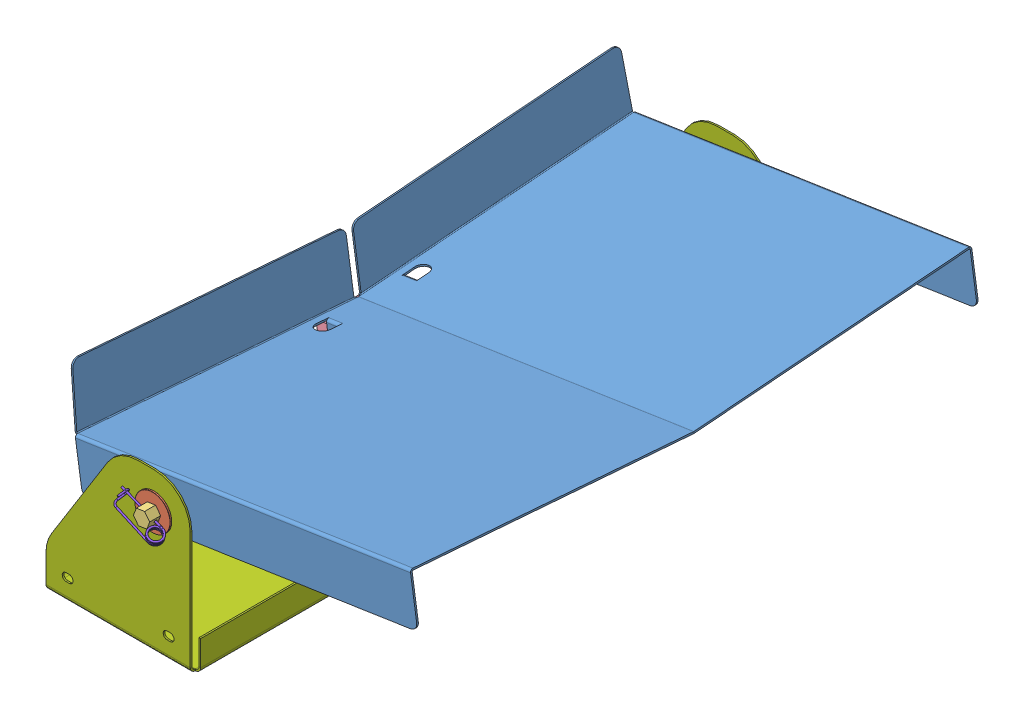
SolidWorks assembly GE-19092, configuration Default. Lengths in mm.
Overall size (322.54 220.42 546.4).
16 component instances, 11 part files, 42 mates.
Components (placement in the parent):
- GE-19085-1: GE-19085 [Magnet_Tray] at (102.7953 126.0608 0) x (0 0 -1) z (0.9887 0.149909 0) size (494.19 94.69 300.92)
- GE-19215-1: GE-19215 [Default] at (31.75 106.5212 249.1842) x (-0.624175 0.781284 0) z (0 0 1) size (31.12 31.12 7.93)
- GE-19215-2: GE-19215 [Default] at (31.75 106.5212 -249.1842) x (0.624175 -0.781284 0) z (0 0 -1) size (31.12 31.12 7.93)
- GE-19096-1: GE-19096 [Default] at (31.75 106.5212 0) x (0.364525 0.931194 0) z (0 0 1) size (14.66 12.7 533.4)
- GE-19099-1: GE-19099 [Default] at (-29.6036 90.187 -0.8681) x (0 0 1) z (-0.982197 -0.187855 0) size (63.5 12.7 38.1)
- Magnet-1: Magnet [Default] at (-29.9177 90.4396 -0.3125) x (0 0 -1) z (-0.984808 -0.173648 0) size (80 24.35 38.1)
- GE-19097-1: GE-19097 [Default] at (-44.45 0 0) x (0 0 1) z (-1 0 0) size (79.38 68.58 38.1)
- GE-19095-2: GE-19095 [Default] x (0 0 1) z (-1 0 0) size (511.18 139.7 136.21)
- pin_bentwire_.0625_1.0625-3: pin_bentwire_.0625_1.0625 [90174A113] at (43.8036 101.9377 -260.4308) x (-0.230622 -0.809824 0.539443) z (-0.952835 0.30035 0.043538) size (6.66 13.94 44.51)
- pin_bentwire_.0625_1.0625-4: pin_bentwire_.0625_1.0625 [90174A113] at (43.7054 101.6867 260.3098) x (0.424884 0.864692 0.267921) z (-0.89993 0.435498 0.021624) size (6.66 13.94 44.51)
- hex_.25_20_.75-2: hex_.25_20_.75 [hex_.25_20_.75] at (-25.4 6.1119 -25.4) x (0 1 0) z (0 0 1) size (23.02 12.83 11.11)
- hex_.25_20_.75-3: hex_.25_20_.75 [hex_.25_20_.75] at (-25.4 6.1119 25.4) x (0 1 0) z (0.188455 0 0.982082) size (23.02 12.83 11.11)
- VHB_Tape-1: VHB_Tape [Default] at (-37.9759 63.0035 -0.3075) x (0 0 -1) z (0.984808 0.173648 0) size (80.01 1.27 12.7)
- VHB_Tape-2: VHB_Tape [Default] at (-12.9618 67.4142 -0.3075) x (0 0 1) z (-0.984808 -0.173648 0) size (80.01 1.27 12.7)
- round_hex_10_32_.625_full-1: round_hex_10_32_.625_full [91306A274] at (-30.7965 96.4239 39.6059) x (0.999933 0.011616 0) z (0 0 1) size (9.17 9.17 18.62)
- round_hex_10_32_.625_full-2: round_hex_10_32_.625_full [91306A274] at (-30.7965 96.4239 -41.342) x (0.523381 -0.852099 0) z (0 0 -1) size (9.17 9.17 18.62)
Mates (geometry in assembly coordinates):
- Coincident13: coincident: plane of GE-19085-1 through (102.7953 126.0608 0) normal (0 0 -1); plane of assembly through (0 0 0) normal (0 0 1)
- Coincident42: coincident: plane of assembly; plane of assembly; plane of Magnet-1 through (-44.45 63.1515 39.6875) normal (0 0 1); plane of GE-19097-1 through (-44.45 0 39.6875) normal (0 0 1)
- Coincident43: coincident: line of assembly; plane of assembly; line of Magnet-1 through (-44.45 63.1515 39.6875) axis (0 0 -1); plane of GE-19097-1 through (-44.45 61.8619 39.6875) normal (-1 0 0)
- Concentric13: concentric: cylinder of assembly; cylinder of assembly; cylinder of GE-19215-2 through (31.75 106.5212 -257.1115) axis (0 0 1) radius 14.2875; cylinder of GE-19095-2 through (31.75 106.5212 -255.5875) axis (0 0 1) radius 14.2812
- Concentric14: concentric: cylinder of assembly; cylinder of assembly; cylinder of GE-19215-1 through (31.75 106.5212 257.1115) axis (0 0 -1) radius 14.2875; cylinder of GE-19095-2 through (31.75 106.5212 -255.5875) axis (0 0 1) radius 14.2812
- Coincident48: coincident: plane of assembly through (0 0 0) normal (0 0 1); plane of GE-19095-2 through (0 0 0) normal (0 0 1); plane of assembly
- Coincident49: coincident: plane of assembly through (0 0 0) normal (1 0 0); plane of GE-19095-2 through (0 0 0) normal (-1 0 0); plane of assembly
- Coincident50: coincident: plane of assembly through (0 0 0) normal (0 1 0); plane of GE-19095-2 through (0 0 0) normal (0 1 0); plane of assembly
- Concentric15: concentric: cylinder of assembly; cylinder of assembly; cylinder of GE-19097-1 through (-25.4 0 25.4) axis (0 -1 0) radius 2.5527; cylinder of GE-19095-2 through (-25.4 0 25.4) axis (0 1 0) radius 3.2639
- Concentric16: concentric: cylinder of assembly; cylinder of assembly; cylinder of GE-19097-1 through (-25.4 0 -25.4) axis (0 -1 0) radius 2.5527; cylinder of GE-19095-2 through (-25.4 0 -25.4) axis (0 1 0) radius 3.2639
- Coincident51: coincident: plane of assembly; plane of assembly; plane of GE-19097-1 through (-44.45 0 39.6875) normal (0 -1 0); plane of GE-19095-2 through (0 0 0) normal (0 1 0)
- Tangent9: tangent: plane of assembly; plane of GE-19096-1 through (36.3267 100.7926 266.7) normal (0.931194 -0.364525 0); face of pin_bentwire_.0625_1.0625-3
- Tangent12: tangent: plane of assembly; plane of GE-19096-1 through (36.3267 100.7926 266.7) normal (0.931194 -0.364525 0); face of pin_bentwire_.0625_1.0625-4
- Coincident56: coincident: unknown of ?; plane of ? through (-29.6283 89.2521 -0.3125) normal (-0.173648 0.984808 0)
- Coincident61: coincident: plane of assembly; plane of assembly; plane of GE-19215-2 through (40.4697 95.6067 -255.5875) normal (0 0 1); plane of GE-19095-2 through (0 0 -255.5875) normal (0 0 -1)
- Coincident63: coincident: plane of assembly; plane of assembly; plane of GE-19215-1 through (23.0303 117.4358 255.5875) normal (0 0 -1); plane of GE-19095-2 through (0 0 255.5875) normal (0 0 1)
- Coincident64: coincident: plane of assembly; plane of assembly; plane of GE-19215-1 through (27.1733 112.2499 257.1115) normal (0.149909 -0.9887 0); plane of GE-19096-1 through (34.4228 113.3491 266.7) normal (-0.149909 0.9887 0)
- Coincident65: coincident: plane of GE-19085-1 through (27.1733 112.2499 252.7917) normal (0.149909 -0.9887 0); plane of GE-19215-1 through (27.1733 112.2499 257.1115) normal (0.149909 -0.9887 0)
- Coincident66: coincident: plane of assembly; plane of assembly; plane of GE-19215-1 through (27.1733 112.2499 257.1115) normal (0.149909 -0.9887 0); plane of GE-19215-2 through (34.4228 113.3491 -257.1115) normal (0.149909 -0.9887 0)
- Coincident67: coincident: plane of assembly; plane of assembly; plane of GE-19215-1 through (24.5005 105.4221 257.1115) normal (0.931194 -0.364525 0); plane of GE-19096-1 through (27.1733 112.2499 266.7) normal (-0.931194 0.364525 0)
- Coincident68: coincident: plane of GE-19085-1 through (24.3936 105.1489 252.7917) normal (0.931194 -0.364525 0); plane of GE-19096-1 through (27.1733 112.2499 266.7) normal (-0.931194 0.364525 0)
- Width2: width: plane of assembly; plane of assembly; plane of assembly; plane of assembly; plane of GE-19096-1 through (31.75 106.5212 266.7) normal (0 0 1); plane of GE-19096-1 through (31.75 106.5212 -266.7) normal (0 0 -1); plane of GE-19095-2 through (0 0 -255.5875) normal (0 0 -1); plane of GE-19095-2 through (0 0 255.5875) normal (0 0 1)
- Coincident71: coincident: unknown of ?; plane of ? through (-29.6283 89.2521 -0.3125) normal (-0.173648 0.984808 0)
- Concentric28: concentric: cylinder of assembly; cylinder of assembly; cylinder of GE-19096-1 through (37.6631 104.2065 -260.35) axis (-0.931194 0.364525 0) radius 1.2573; cylinder of pin_bentwire_.0625_1.0625-3 through (41.6769 102.6353 -260.35) axis (-0.931194 0.364525 0) radius 0.7366
- Concentric29: concentric: cylinder of assembly; cylinder of assembly; cylinder of GE-19096-1 through (37.6631 104.2065 260.35) axis (-0.931194 0.364525 0) radius 1.2573; cylinder of pin_bentwire_.0625_1.0625-4 through (41.6769 102.6353 260.35) axis (-0.931194 0.364525 0) radius 0.7366
- Concentric30: concentric: cylinder of assembly; cylinder of assembly; cylinder of GE-19097-1 through (-25.4 0 -25.4) axis (0 -1 0) radius 2.5527; cylinder of hex_.25_20_.75-2 through (-25.4 -1.4287 -25.4) axis (0 1 0) radius 3.175
- Coincident72: coincident: plane of assembly; plane of assembly; plane of GE-19095-2 through (0 -1.4287 0) normal (0 -1 0); plane of hex_.25_20_.75-2 through (-28.6079 -1.4287 -19.8438) normal (0 1 0)
- Concentric31: concentric: cylinder of assembly; cylinder of assembly; cylinder of GE-19097-1 through (-25.4 0 25.4) axis (0 -1 0) radius 2.5527; cylinder of hex_.25_20_.75-3 through (-25.4 -1.4287 25.4) axis (0 1 0) radius 3.175
- Coincident73: coincident: plane of assembly; plane of assembly; plane of GE-19095-2 through (0 -1.4287 0) normal (0 -1 0); plane of hex_.25_20_.75-3 through (-27.5033 -1.4287 31.4612) normal (0 1 0)
- Width4: width: plane of GE-19099-1 through (-50.7002 99.0822 30.8819) normal (0 0 1); plane of GE-19099-1 through (-50.7002 99.0822 -32.6181) normal (0 0 -1); plane of GE-19085-1 through (97.5504 160.653 -35.6016) normal (0 0 -1); plane of GE-19085-1 through (97.5455 160.6853 33.8655) normal (0 0 1)
- Coincident76: coincident: plane of assembly; plane of assembly; plane of Magnet-1 through (-25.6894 66.4595 -0.3125) normal (0.173648 -0.984808 0); plane of VHB_Tape-2 through (-13.1824 68.6649 -0.3075) normal (-0.173648 0.984808 0)
- Coincident77: coincident: plane of assembly; plane of assembly; plane of Magnet-1 through (-6.9288 69.7675 39.6875) normal (0.984808 0.173648 0); plane of VHB_Tape-2 through (-6.9288 69.7675 -40.3125) normal (0.984808 0.173648 0)
- Coincident78: coincident: plane of assembly; plane of assembly; plane of Magnet-1 through (-44.45 63.1515 -40.3125) normal (0 0 -1); plane of VHB_Tape-2 through (-19.4359 67.5622 -40.3125) normal (0 0 -1)
- Coincident79: coincident: plane of assembly; plane of assembly; plane of Magnet-1 through (-25.6894 66.4595 -0.3125) normal (0.173648 -0.984808 0); plane of VHB_Tape-1 through (-38.1965 64.2542 -0.3075) normal (-0.173648 0.984808 0)
- Coincident80: coincident: plane of assembly; plane of assembly; plane of Magnet-1 through (-44.45 63.1515 39.6875) normal (-0.984808 -0.173648 0); plane of VHB_Tape-1 through (-44.45 63.1515 39.6975) normal (-0.984808 -0.173648 0)
- Coincident81: coincident: plane of assembly; plane of assembly; plane of Magnet-1 through (-44.45 63.1515 -40.3125) normal (0 0 -1); plane of VHB_Tape-1 through (-31.9429 65.3569 -40.3125) normal (0 0 -1)
- Coincident82: coincident: plane of assembly; plane of assembly; plane of GE-19097-1 through (-6.35 68.58 39.6875) normal (-0.173648 0.984808 0); plane of VHB_Tape-2 through (-12.9618 67.4142 -0.3075) normal (0.173648 -0.984808 0)
- Distance1: distance = 3.175 mm: plane of round_hex_10_32_.625_full-1 through (-30.7432 91.8395 37.0405) normal (0 0 -1); plane of GE-19085-1 through (97.5455 160.6853 33.8655) normal (0 0 1)
- Distance2: distance = 3.175 mm: plane of GE-19085-1 through (97.5504 160.653 -35.6016) normal (0 0 -1); plane of round_hex_10_32_.625_full-2 through (-26.8898 98.8234 -38.7766) normal (0 0 1)
- Concentric36: concentric: cylinder of GE-19085-1 through (-30.7965 96.4239 -35.6016) axis (0 0 -1) radius 2.5798; cylinder of round_hex_10_32_.625_full-2 through (-30.7965 96.4239 -22.9016) axis (0 0 1) radius 2.413
- Concentric39: concentric: cylinder of assembly; cylinder of assembly; cylinder of GE-19099-1 through (-30.7965 96.4239 -32.6181) axis (0 0 -1) radius 2.0193; cylinder of round_hex_10_32_.625_full-2 through (-30.7965 96.4239 -22.9016) axis (0 0 1) radius 2.413
- Concentric40: concentric: cylinder of assembly; cylinder of assembly; cylinder of GE-19099-1 through (-30.7965 96.4239 30.8819) axis (0 0 1) radius 2.0193; cylinder of round_hex_10_32_.625_full-1 through (-30.7965 96.4239 21.1655) axis (0 0 -1) radius 2.413
